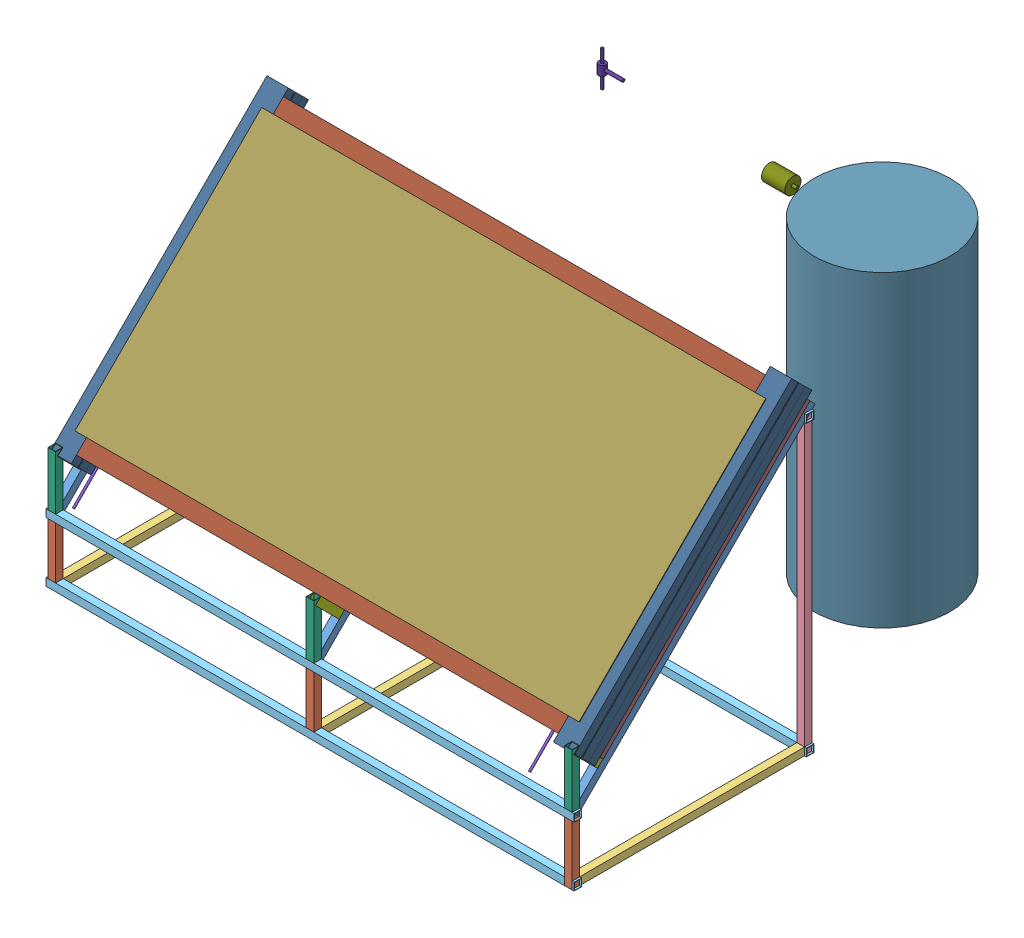
SolidWorks assembly final_assembly, configuration Default. Lengths in mm.
Overall size (2200 1390.98 2143.74).
44 component instances, 17 part files, 9 mates.
Components (placement in the parent):
- frame_assembly-1: frame_assembly [Default] at origin size (2200 1269.95 1012.4)
  - 1.25in_square_tubing_1.4m-1: 1.25in_square_tubing_1.4m [Default] at (0 355.2814 -506.8232) x (1 0 0) z (0 -0.707107 0.707107) size (31.75 31.75 1400)
  - 1.25in_square_tubing_1.4m-2: 1.25in_square_tubing_1.4m [Default] at (1075.875 355.2814 -506.8232) x (1 0 0) z (0 -0.707107 0.707107) size (31.75 31.75 1400)
  - 1.25in_square_tubing_1.4m-3: 1.25in_square_tubing_1.4m [Default] at (-1075.875 355.2814 -506.8232) x (1 0 0) z (0 -0.707107 0.707107) size (31.75 31.75 1400)
  - 1.25in_square_tubing_.3m-1: 1.25in_square_tubing_.3m [Default] at (-1075.875 -903.4428 478.4766) x (1 0 0) z (0 1 0) size (31.75 31.75 280)
  - 1.25in_square_tubing_.3m-2: 1.25in_square_tubing_.3m [Default] at (0 -903.4428 478.4766) x (1 0 0) z (0 1 0) size (31.75 31.75 280)
  - 1.25in_square_tubing_.3m-4: 1.25in_square_tubing_.3m [Default] at (1075.875 -903.4428 478.4766) x (1 0 0) z (0 1 0) size (31.75 31.75 280)
  - 1.25in_square_tubing_1m-1: 1.25in_square_tubing_1m [Default] at (0 -887.5678 -505.6484) size (31.75 31.75 1000)
  - 1.25in_square_tubing_1.3m-1: 1.25in_square_tubing_1.3m [Default] at (0 331.5572 -489.7734) x (-1 0 0) z (0 -1 0) size (31.75 31.75 1235)
  - 1.25in_square_tubing_1.3m-2: 1.25in_square_tubing_1.3m [Default] at (-1075.875 331.5572 -489.7734) x (-1 0 0) z (0 -1 0) size (31.75 31.75 1235)
  - 1.25in_square_tubing_1m-2: 1.25in_square_tubing_1m [Default] at (-1075.875 -887.5678 -505.6484) size (31.75 31.75 1000)
  - 1.25in_square_tubing_1.3m-4: 1.25in_square_tubing_1.3m [Default] at (1075.875 331.5572 -489.7734) x (-1 0 0) z (0 -1 0) size (31.75 31.75 1235)
  - 1.25in_square_tubing_1m-4: 1.25in_square_tubing_1m [Default] at (1075.875 -887.5678 -505.6484) size (31.75 31.75 1000)
  - 1.25in_square_tubing_2.2m-1: 1.25in_square_tubing_2.2m [Default] at (1100 315.6822 -489.7734) x (0 0 1) z (-1 0 0) size (31.75 31.75 2200)
  - 1.25in_square_tubing_2.2m-2: 1.25in_square_tubing_2.2m [Default] at (1100 -887.5678 -489.7734) x (0 0 1) z (-1 0 0) size (31.75 31.75 2200)
  - 1.25in_square_tubing_2.2m-3: 1.25in_square_tubing_2.2m [Default] at (1100 -887.5678 478.4766) x (0 0 -1) z (-1 0 0) size (31.75 31.75 2200)
  - 1.25in_square_tubing_2.2m-5: 1.25in_square_tubing_2.2m [Default] at (-1100 -639.3178 478.4766) x (0 0 -1) z (1 0 0) size (31.75 31.75 2200)
  - 1.25in_square_tubing_.1m-1: 1.25in_square_tubing_.1m [Default] at (0 -398.4428 478.4766) x (1 0 0) z (0 -1 0) size (31.75 31.75 225)
  - 1.25in_square_tubing_.1m-2: 1.25in_square_tubing_.1m [Default] at (1075.875 -398.4428 478.4766) x (1 0 0) z (0 -1 0) size (31.75 31.75 225)
  - 1.25in_square_tubing_.1m-3: 1.25in_square_tubing_.1m [Default] at (-1075.875 -398.4428 478.4766) x (1 0 0) z (0 -1 0) size (31.75 31.75 225)
  - 1.25in_square_tubing_.15m-1: 1.25in_square_tubing_.15m [Default] at (-1075.875 -506.2931 377.2019) x (1 0 0) z (0 0.707107 0.707107) size (31.75 31.75 140)
  - 1.25in_square_tubing_.15m-4: 1.25in_square_tubing_.15m [Default] at (0 -506.2931 377.2019) x (1 0 0) z (0 0.707107 0.707107) size (31.75 31.75 140)
  - 1.25in_square_tubing_.15m-5: 1.25in_square_tubing_.15m [Default] at (1075.875 -506.2931 377.2019) x (1 0 0) z (0 0.707107 0.707107) size (31.75 31.75 140)
- solar_collector-2: solar_collector [Default] at (0 0.5301 -0.5301) x (1 0 0) z (0 -0.707107 0.707107) size (2185.74 141.11 1388.9)
  - serpentine_manifold-1: serpentine_manifold [Default] at (-0.0012 0 0) size (1907.94 7.94 1253.97)
  - absorber-1: absorber [Default] at (-0.0012 3.9688 0) size (2100 4.76 1100)
  - 2x4in_width-1: 2x4in_width [Default] at (-1048.42 3.9688 0) size (88.9 38.1 1277.8)
  - 2x4in_width-4: 2x4in_width [Default] at (-1048.42 46.8312 0) size (88.9 38.1 1277.8)
  - 2x4in_width-16: 2x4in_width [Default] at (1048.4175 8.7312 0) x (-1 0 0) z (0 0 1) size (88.9 38.1 1277.8)
  - 2x4in_width-19: 2x4in_width [Default] at (1048.4175 -34.1313 0) x (-1 0 0) z (0 0 1) size (88.9 38.1 1277.8)
  - 2x4in_width-20: 2x4in_width [Default] at (1048.4175 -34.1313 0) size (88.9 38.1 1277.8)
  - 2x4in_width-21: 2x4in_width [Default] at (-1048.42 -34.1313 0) size (88.9 38.1 1277.8)
  - 2x4in_length-20: 2x4in_length [Default] at (-0.0012 3.9688 -565.15) x (0 0 1) z (-1 0 0) size (88.9 38.1 2007.94)
  - 2x4in_length-21: 2x4in_length [Default] at (-0.0012 46.8312 -565.15) x (0 0 1) z (-1 0 0) size (88.9 38.1 2007.94)
  - 2x4in_length-22: 2x4in_length [Default] at (-0.0012 3.9688 565.15) x (0 0 -1) z (1 0 0) size (88.9 38.1 2007.94)
  - 2x4in_length-23: 2x4in_length [Default] at (-0.0012 46.8312 565.15) x (0 0 1) z (-1 0 0) size (88.9 38.1 2007.94)
  - 2x4in_length-24: 2x4in_length [Default] at (-0.0012 -34.1313 565.15) x (0 0 1) z (-1 0 0) size (88.9 38.1 2007.94)
  - 2x4in_length-26: 2x4in_length [Default] at (-0.0012 -34.1313 -565.15) x (0 0 1) z (-1 0 0) size (88.9 38.1 2007.94)
  - glass-1: glass [Default] at (-0.0012 46.8312 0) x (0 0 1) z (-1 0 0) size (1100 3 2100)
  - 4x8ft_plywood_board-1: 4x8ft_plywood_board [Default] at (0 -91.2812 0) size (2185.74 19.05 1219.2)
- hot_water_tank-1: hot_water_tank [Default] at (592.87 -903.4428 -1296.128) size (565.15 1282.7 565.15)
- compressor-1: compressor [Default] at (-592.87 -903.4428 -1296.128) size (139.45 382.52 139.45)
- filter_drier-1: filter_drier [Default] at (177.132 312.2668 -1291.6067) size (134.37 67.06 67.06)
- exv-1: exv [Default] at (-571.8934 334.6188 -1295.0395) size (103 148 30)
Mates (geometry in assembly coordinates):
- Coincident7: coincident aligned: plane of compressor-1 through (-101.4141 254.3532 -1131.3606) normal (0.512264 -0.840882 -0.174651); plane of hot_water_tank-1 through (183.6207 -661.3629 204.8204) normal (0.512264 -0.840882 -0.174651)
- Coincident11: coincident aligned: plane of compressor-1; plane of hot_water_tank-1
- Distance11: distance = 500 mm: plane of compressor-1 through (-592.87 -903.4428 -1296.128) normal (1 0 0); line of solar_collector-2/4x8ft_plywood_board-1 through (-1092.87 367.0368 -496.128) axis (0 -0.707107 0.707107)
- Distance12: distance = 500 mm: plane of hot_water_tank-1 through (592.87 -903.4428 -1296.128) normal (1 0 0); line of solar_collector-2/4x8ft_plywood_board-1 through (1092.87 -495.0678 365.9766) axis (0 0.707107 -0.707107)
- Distance13: distance = 800 mm: plane of hot_water_tank-1 through (592.87 -903.4428 -1296.128) normal (0 0 1); point of solar_collector-2/4x8ft_plywood_board-1
- Coincident12: coincident anti-aligned: plane of frame_assembly-1/1.25in_square_tubing_1.4m-3 through (-1091.75 -623.4428 494.3516) normal (0 0.707107 0.707107); plane of solar_collector-2/4x8ft_plywood_board-1 through (0 -64.0155 -65.0757) normal (0 -0.707107 -0.707107)
- Coincident13: coincident anti-aligned: plane of frame_assembly-1/1.25in_square_tubing_.15m-1 through (-1091.75 -396.0728 464.9716) normal (0 0.707107 -0.707107); plane of solar_collector-2/2x4in_length-24 through (-1003.97 -454.6566 406.3878) normal (0 -0.707107 0.707107)
- Symmetric1: symmetric aligned: plane of frame_assembly-1/1.25in_square_tubing_1.4m-3 through (-1091.75 -623.4428 494.3516) normal (-1 0 0); plane of solar_collector-2 through (1091.75 -623.4428 494.3516) normal (1 0 0); plane of frame_assembly-1/1.25in_square_tubing_1.4m-2 through (0 0.5301 -0.5301) normal (1 0 0)
- Coincident14: coincident aligned: plane of frame_assembly-1/1.25in_square_tubing_1m-1 through (-15.875 -903.4428 494.3516) normal (0 -1 0); plane of hot_water_tank-1 through (592.87 -903.4428 -1296.128) normal (0 -1 0)
